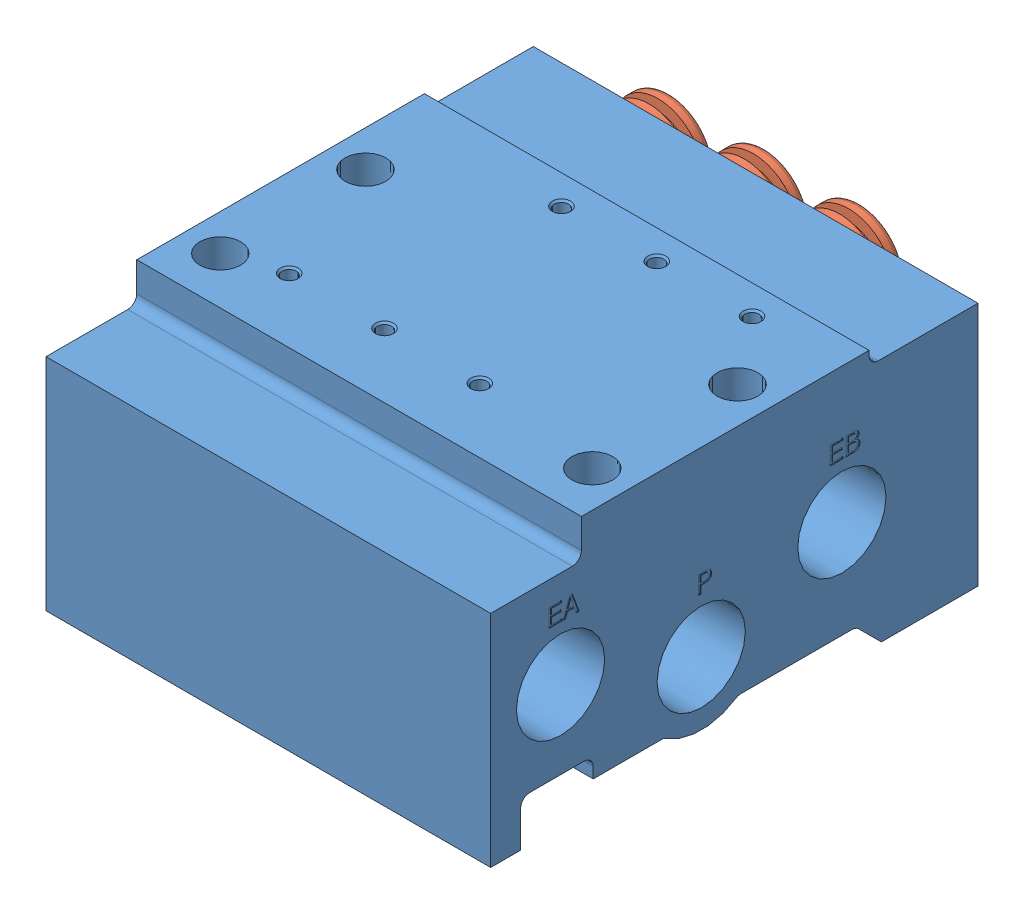
SolidWorks assembly 3 Station Manifold 217-2951, configuration Default. Lengths in mm.
Overall size (49 28.5 58.2).
7 component instances, 2 part files, 0 mates.
Components (placement in the parent):
- Copy of 217-2951-001 Rev1_41^3 Station Manifold 217-2951-1: Copy of 217-2951-001 Rev1_41^3 Station Manifold 217-2951 [Default] at origin size (49 28.5 53.7) (virtual)
- Copy of 217-2951-002 Rev1_1000-50A-N7^3 Station Manifold 217-2951-1: Copy of 217-2951-002 Rev1_1000-50A-N7^3 Station Manifold 217-2951 [Default] at (-10.5 -22 -15.65) x (1 0 0) z (0 0 -1) size (10 10 15.7) (virtual)
- Copy of 217-2951-002 Rev1_1000-50A-N7^3 Station Manifold 217-2951-2: Copy of 217-2951-002 Rev1_1000-50A-N7^3 Station Manifold 217-2951 [Default] at (-17.5 -7.8 -15.65) x (1 0 0) z (0 0 -1) size (10 10 15.7) (virtual)
- Copy of 217-2951-002 Rev1_1000-50A-N7^3 Station Manifold 217-2951-3: Copy of 217-2951-002 Rev1_1000-50A-N7^3 Station Manifold 217-2951 [Default] at (-21 -22 -15.65) x (1 0 0) z (0 0 -1) size (10 10 15.7) (virtual)
- Copy of 217-2951-002 Rev1_1000-50A-N7^3 Station Manifold 217-2951-4: Copy of 217-2951-002 Rev1_1000-50A-N7^3 Station Manifold 217-2951 [Default] at (-28 -7.8 -15.65) x (1 0 0) z (0 0 -1) size (10 10 15.7) (virtual)
- Copy of 217-2951-002 Rev1_1000-50A-N7^3 Station Manifold 217-2951-5: Copy of 217-2951-002 Rev1_1000-50A-N7^3 Station Manifold 217-2951 [Default] at (-31.5 -22 -15.65) x (1 0 0) z (0 0 -1) size (10 10 15.7) (virtual)
- Copy of 217-2951-002 Rev1_1000-50A-N7^3 Station Manifold 217-2951-6: Copy of 217-2951-002 Rev1_1000-50A-N7^3 Station Manifold 217-2951 [Default] at (-38.5 -7.8 -15.65) x (1 0 0) z (0 0 -1) size (10 10 15.7) (virtual)
